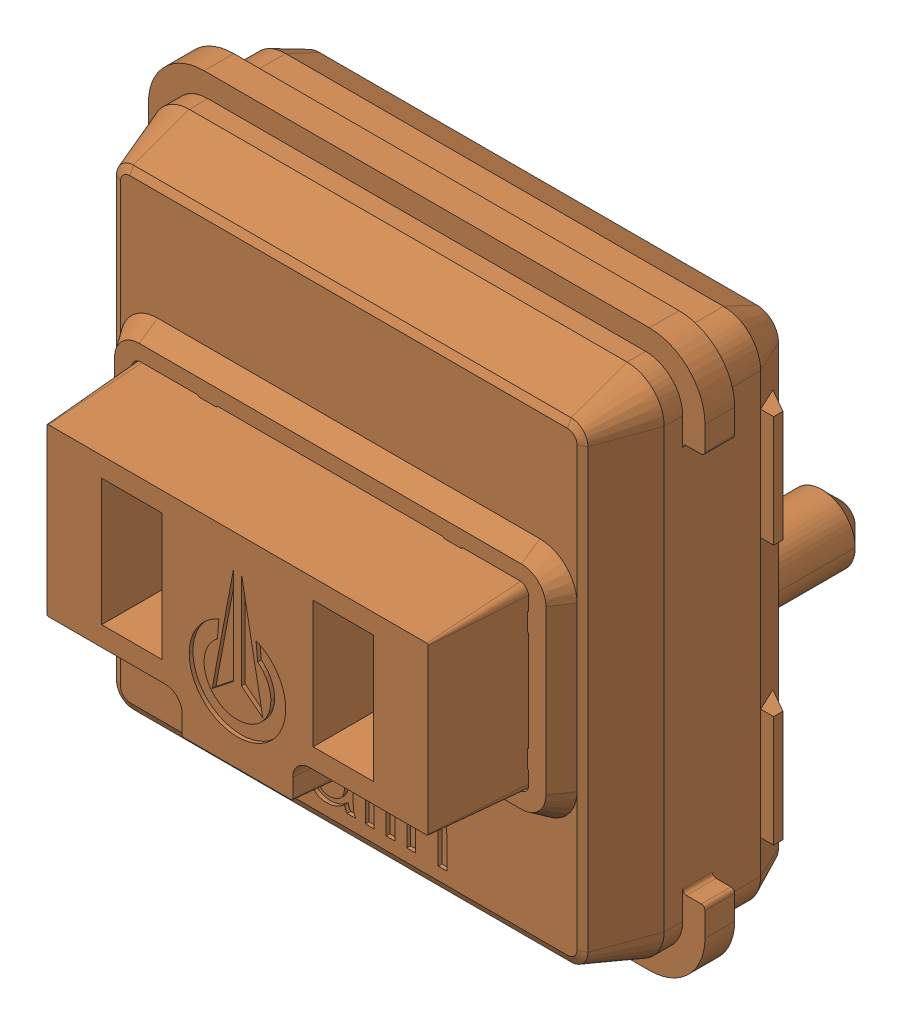
SolidWorks assembly SW8_1.step, configuration Default. Lengths in mm.
Overall size (15 15 11.1).
2 component instances, 2 part files, 0 mates.
Components (placement in the parent):
- WS2812-2020_1.step-3: WS2812-2020_1.step [Default] at (466.1066 231.0345 0.3) x (1 0 0) z (0 -1 0) size (2.2 0.86 2)
- Kailh LP Choc Burnt Orange_1.step-3: Kailh LP Choc Burnt Orange_1.step [Default] at (466 226.3933 2.7) x (0 -1 0) z (-1 0 0) size (15 11.1 15)
